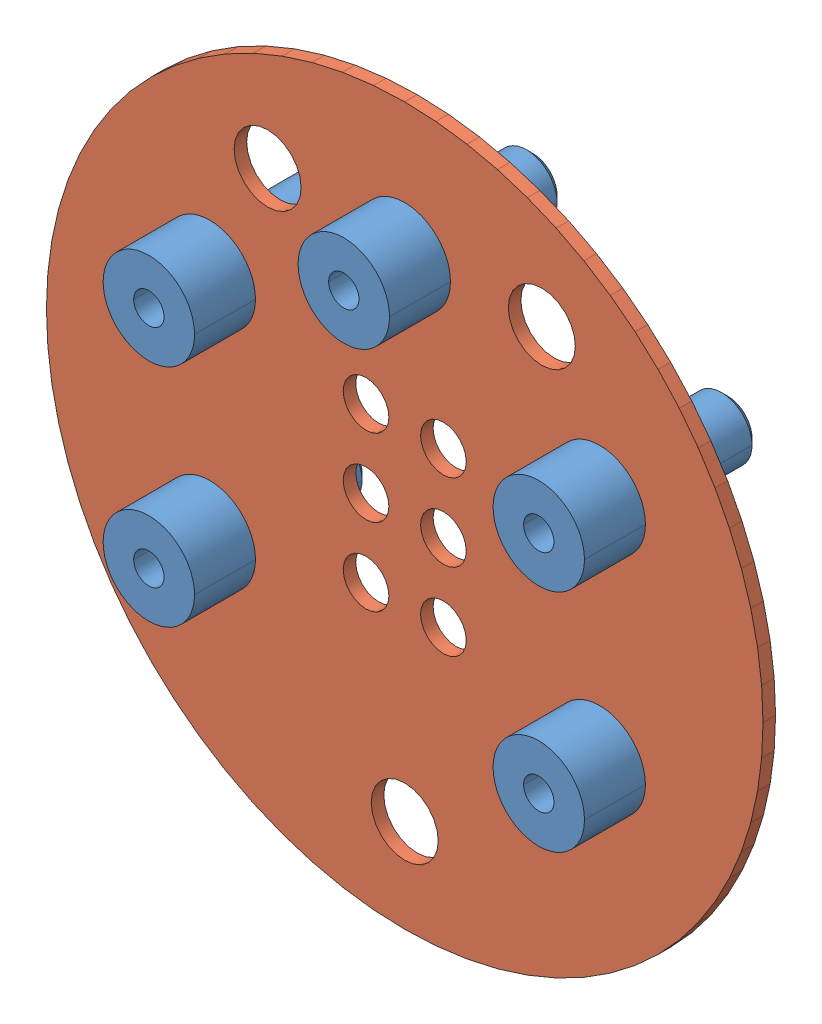
SolidWorks assembly 传感器插座板, configuration Default. Lengths in mm.
Overall size (23.52 23.52 6.2).
7 component instances, 2 part files, 0 mates.
Components (placement in the parent):
- JP2.step-1: JP2.step [Default] at origin size (15.8 14.1 6.2)
  - __________.step-1: __________.step [Default] at (-6.3999 3.7001 0) size (3 3 6.2)
  - __________.step-2: __________.step [Default] at (6.4001 -3.7 0) size (3 3 6.2)
  - __________.step-3: __________.step [Default] at (-6.3999 -3.6999 0) size (3 3 6.2)
  - __________.step-4: __________.step [Default] at (6.4001 3.7001 0) size (3 3 6.2)
  - __________.step-5: __________.step [Default] at (0.0001 7.4001 0) size (3 3 6.2)
- Board^传感器插座板-1: Board^传感器插座板 [Default] at (0 0 -0.4115) size (23.52 23.52 0.41) (virtual)
